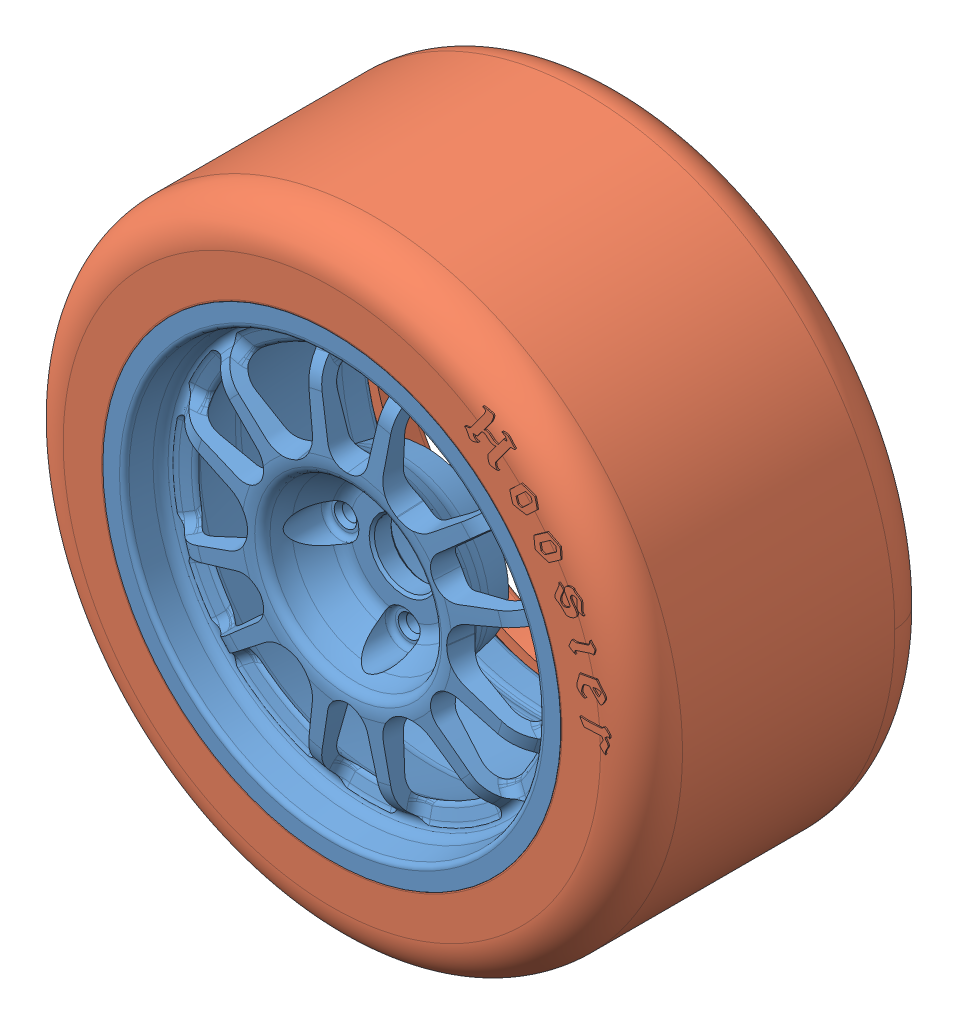
SolidWorks assembly Wheel and Tire Assembly, configuration Default. Lengths in mm.
Overall size (484.14 484.14 231.18).
2 component instances, 2 part files, 7 mates.
Components (placement in the parent):
- OZ Al 7x13 Wheel-1: OZ Al 7x13 Wheel [Default] at (0 0 19.8) x (-1 0 0) z (0 0 1) size (359.65 359.65 190.61)
- Hoosier 20.5x7x13 R25B A2500 Tire-2: Hoosier 20.5x7x13 R25B A2500 Tire [Default] at origin size (484.14 484.14 231.18)
Mates (geometry in assembly coordinates):
- Coincident5: coincident anti-aligned: plane of OZ Al 7x13 Wheel-1; plane of assembly through (0 0 0) normal (0 1 0)
- Parallel1: parallel aligned: plane of OZ Al 7x13 Wheel-1 through (0 0 22.2459) normal (0 0 1); plane of assembly through (0 0 0) normal (0 0 1)
- Coincident7: coincident anti-aligned: plane of OZ Al 7x13 Wheel-1; plane of assembly through (0 0 0) normal (1 0 0)
- Coincident8: coincident aligned: plane of Hoosier 20.5x7x13 R25B A2500 Tire-2 through (0 0 0) normal (0 1 0); plane of assembly
- Coincident9: coincident aligned: plane of Hoosier 20.5x7x13 R25B A2500 Tire-2 through (0 0 0) normal (1 0 0); plane of assembly
- Coincident10: coincident aligned: plane of Hoosier 20.5x7x13 R25B A2500 Tire-2 through (0 0 0) normal (0 0 1); plane of assembly
- Coincident12: coincident aligned: plane of OZ Al 7x13 Wheel-1 through (89.53 0 115) normal (0 0 1); plane of Hoosier 20.5x7x13 R25B A2500 Tire-2 through (212.52 -212.52 115) normal (0 0 1)
